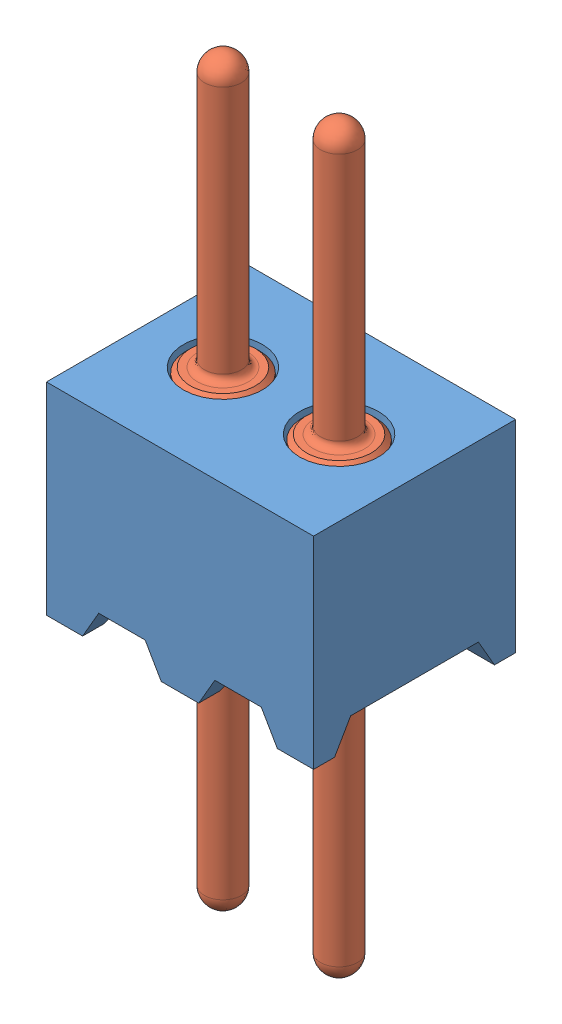
SolidWorks assembly mill-max-850-10-002-10-001000, configuration Default. Lengths in mm.
Overall size (2.92 8.1 2.21).
3 component instances, 2 part files, 0 mates.
Components (placement in the parent):
- mill-max-850-10-002-10-001000_P8XX-18-011-02-000000(P802-18-011-02-000000)-1: mill-max-850-10-002-10-001000_P8XX-18-011-02-000000(P802-18-011-02-000000) [Default] at origin size (2.92 2.21 2.21)
- mill-max-850-10-002-10-001000_4006PIN(4006-0-00-15-00-00-03-0)-1: mill-max-850-10-002-10-001000_4006PIN(4006-0-00-15-00-00-03-0) [Default] at (0.8255 2.9972 -1.1049) x (0 -1 0) z (0 0 1) size (8.1 1.11 0.92)
- mill-max-850-10-002-10-001000_4006PIN(4006-0-00-15-00-00-03-0)-2: mill-max-850-10-002-10-001000_4006PIN(4006-0-00-15-00-00-03-0) [Default] at (2.0955 2.9972 -1.1049) x (0 -1 0) z (0 0 1) size (8.1 1.11 0.92)
